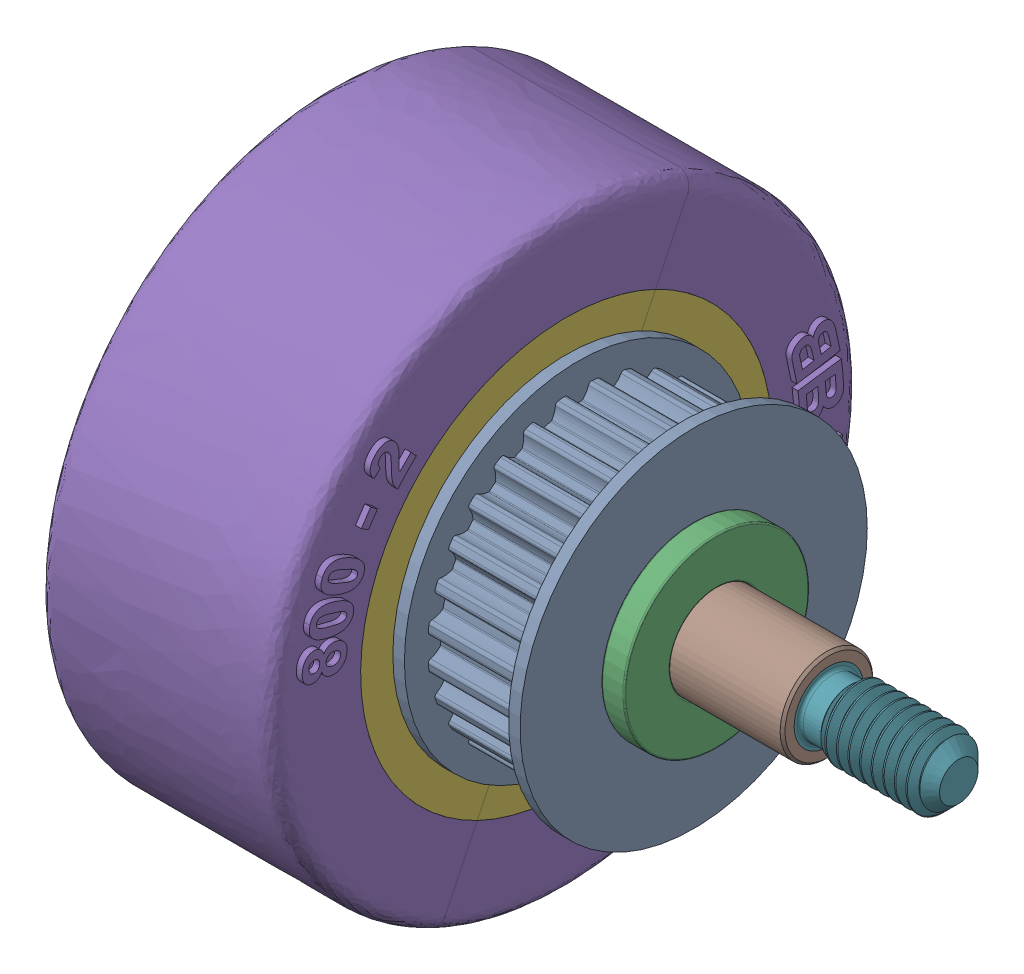
SolidWorks assembly VM-1003-FINAL-WHEEL-ASSEMBLY, configuration Default. Lengths in mm.
Overall size (62.46 67.81 67.81).
6 component instances, 4 part files, 5 mates.
Components (placement in the parent):
- VM-1001-PULLEY-HUB-ASSEMBLY-1: VM-1001-PULLEY-HUB-ASSEMBLY [Default] at (-8.0507 3.9396 1.5717) size (35.32 30 30)
  - VM-1002-HUB-PULLEY-1: VM-1002-HUB-PULLEY [Default] at (5.3489 -5.9159 -2.0287) size (31.32 30 30)
  - 6659K115_Oil-Embedded Flanged Sleeve Bearing-1: 6659K115_Oil-Embedded Flanged Sleeve Bearing [6659K115] at (14.3835 -4.9141 -1.6722) x (0 -0.721211 0.692716) z (0 -0.692716 -0.721211) size (16 6 16)
  - 6659K115_Oil-Embedded Flanged Sleeve Bearing-2: 6659K115_Oil-Embedded Flanged Sleeve Bearing [6659K115] at (-20.9365 -4.9141 -1.6722) x (0 0.98406 -0.177836) z (0 -0.177836 -0.98406) size (16 6 16)
- T81P-20-1: T81P-20 [Default] at (-6.6672 -0.9745 -0.1005) x (0 -0.901207 0.433388) z (-1 0 0) size (50.81 50.81 21.34)
- 92981A250_Alloy Steel Shoulder Screws-1: 92981A250_Alloy Steel Shoulder Screws [92981A250] at (-3.8737 -0.9745 -0.1005) x (0 0.940602 -0.339512) z (-1 0 0) size (13 13 62.46)
Mates (geometry in assembly coordinates):
- Coincident1: coincident: plane of VM-1001-PULLEY-HUB-ASSEMBLY-1/VM-1002-HUB-PULLEY-1 through (-14.2872 -12.9507 -1.5613) normal (0 -0.901207 0.433388); plane of T81P-20-1 through (-14.2847 -7.3108 10.1667) normal (0 0.901207 -0.433388)
- Tangent3: tangent: plane of assembly; plane of VM-1001-PULLEY-HUB-ASSEMBLY-1/VM-1002-HUB-PULLEY-1 through (-6.6672 -0.9745 -0.1005) normal (-1 0 0); face of T81P-20-1
- Coincident2: coincident anti-aligned: plane of VM-1001-PULLEY-HUB-ASSEMBLY-1/VM-1002-HUB-PULLEY-1 through (-14.2872 0.4863 -12.0767) normal (0 -0.433388 -0.901207); plane of T81P-20-1 through (-14.2847 -11.2417 -6.4368) normal (0 0.433388 0.901207)
- Concentric1: concentric: cylinder of VM-1001-PULLEY-HUB-ASSEMBLY-1/6659K115_Oil-Embedded Flanged Sleeve Bearing-2 through (-22.9872 -0.9745 -0.1005) axis (-1 0 0) radius 4.005; cylinder of 92981A250_Alloy Steel Shoulder Screws-1 through (-45.9529 -0.9745 -0.1005) axis (-1 0 0) radius 4
- Coincident3: coincident anti-aligned: plane of VM-1001-PULLEY-HUB-ASSEMBLY-1/6659K115_Oil-Embedded Flanged Sleeve Bearing-2 through (-28.9872 -0.9745 -0.1005) normal (-1 0 0); plane of 92981A250_Alloy Steel Shoulder Screws-1 through (-28.9872 -3.1813 -6.2144) normal (1 0 0)
